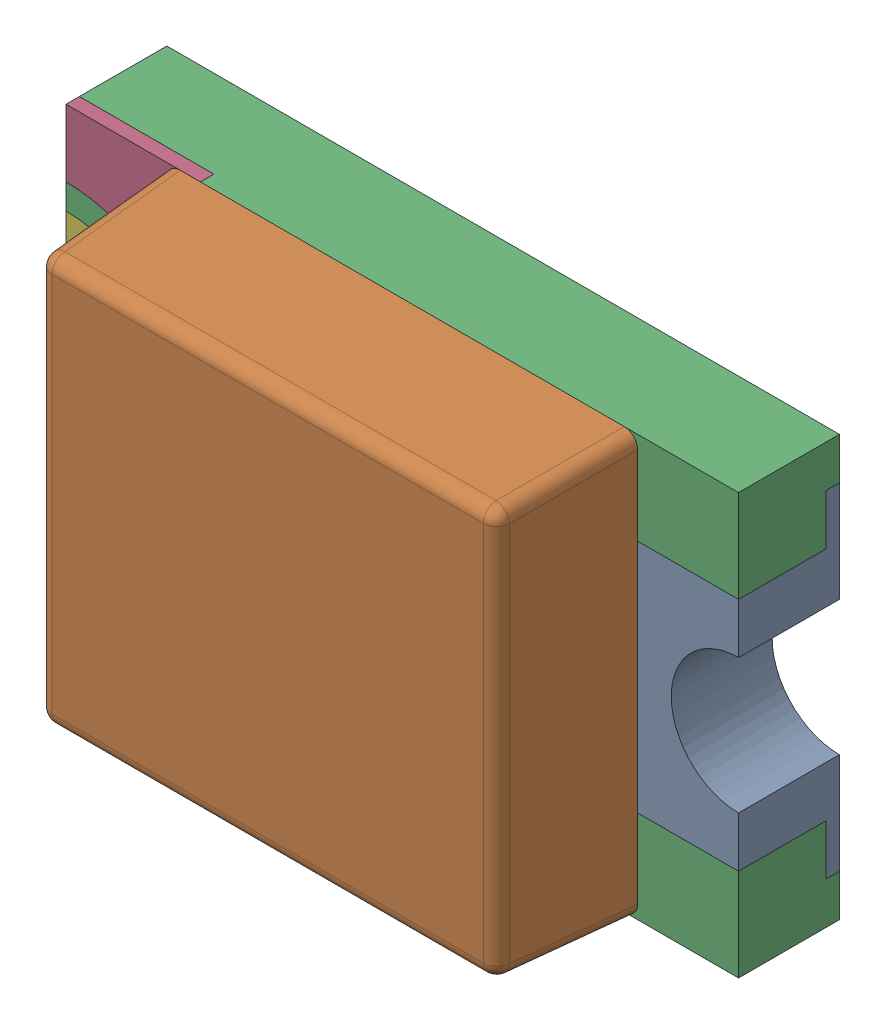
SolidWorks assembly D4, configuration Standard. Lengths in mm.
Overall size (2 1.25 0.7).
7 component instances, 5 part files, 0 mates.
Components (placement in the parent):
- WL-SMCW_0805_LED-1: WL-SMCW_0805_LED [Standard] at (12.1202 26.3802 -0.02) x (1 0 0) z (0 0 1) size (2 1.25 0.7)
  - base-1: base [Standard] at (0.8 0 0) x (-1 0 0) z (0 0 1) size (0.4 1 0.3)
  - cover-1: cover [Standard] at (0 0 0.3) size (1.4 1.25 0.4)
  - housing_3-1: housing_3 [Standard] at origin size (2 1.25 0.3)
  - marking-1: marking [Standard] at (-0.8 0.525 0.26) size (0.4 0.48 0.04)
  - marking-2: marking [Standard] at (-0.8 -0.525 0.3) x (1 0 0) z (0 0 -1) size (0.4 0.48 0.04)
  - base_2-1: base_2 [Standard] at (-0.8 0 0) size (0.4 1 0.3)
